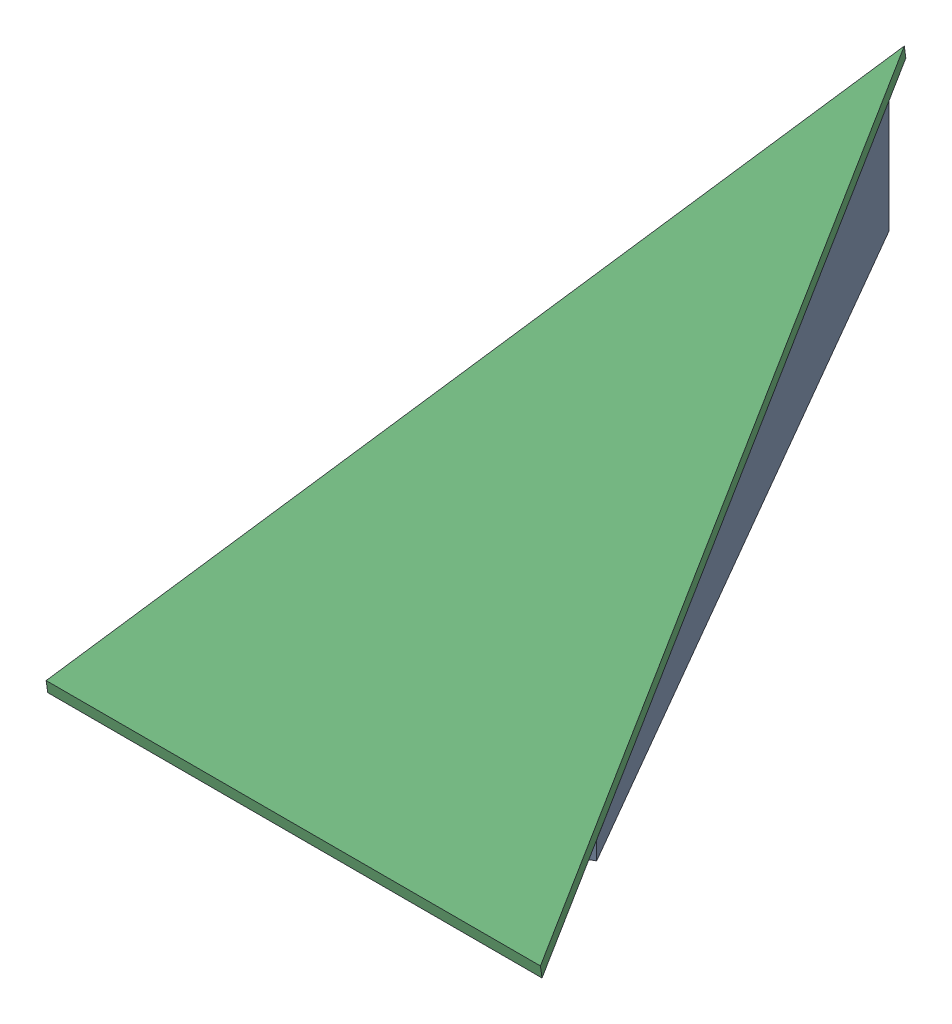
SolidWorks assembly GE-16140_ASM, configuration Default. Lengths in mm.
Overall size (552.73 147.3 961.36).
3 component instances, 3 part files, 0 mates.
Components (placement in the parent):
- GE-16140-02-1: GE-16140-02 [Default] at origin size (457.2 129.07 779.19)
- GE-16140-03-1: GE-16140-03 [Default] at origin size (12.7 127.82 772.85)
- GE-16140-01-1: GE-16140-01 [Default] at (0 134.7215 -1.7651) x (1 0 0) z (0 -0.13903 0.990288) size (552.73 12.7 969.01)
